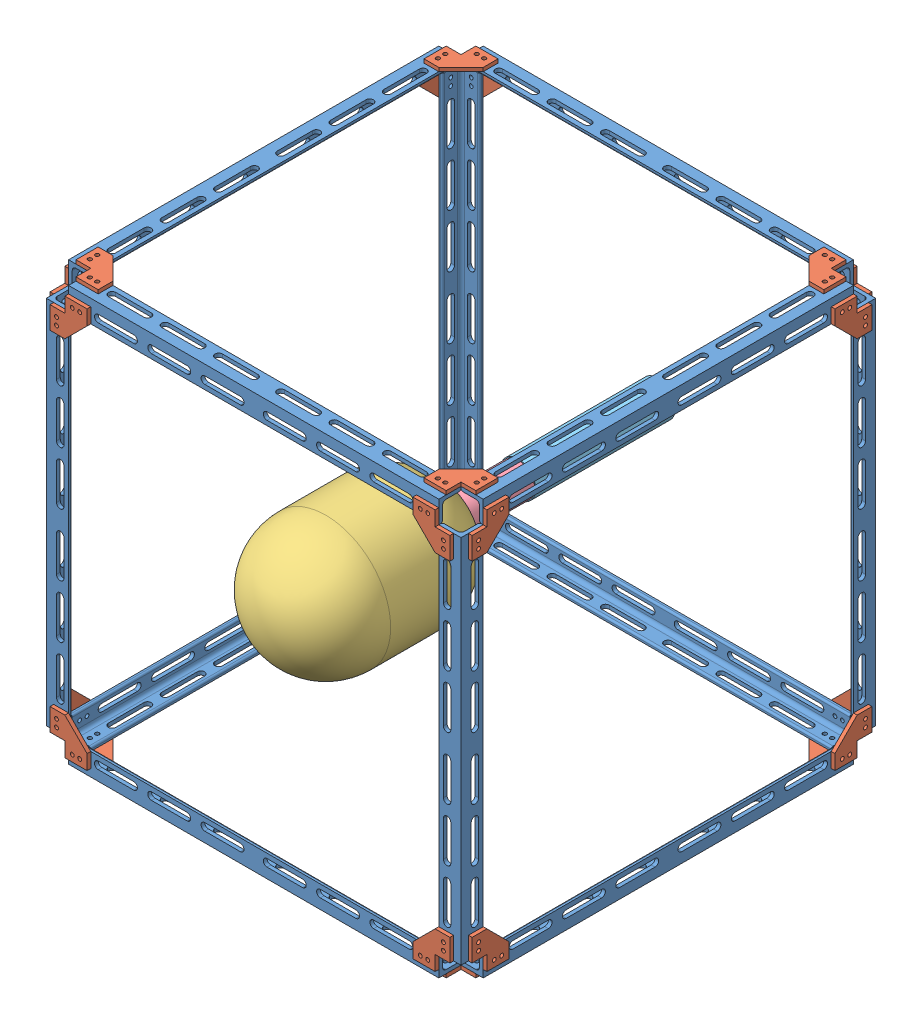
SolidWorks assembly Assem3, configuration Default. Lengths in mm.
Overall size (361.95 361.95 361.95).
41 component instances, 5 part files, 7 mates.
Components (placement in the parent):
- Outer struct 14 in side length-1: Outer struct 14 in side length [Default] at origin size (361.95 361.95 361.95)
  - WIP 14 inch .75 L rod-1: WIP 14 inch .75 L rod [8982K281] at (-9.525 9.525 0) size (19.05 19.05 317.5)
  - WIP bracket for .75 L bar-1: WIP bracket for .75 L bar [Default] at (-44.45 -3.175 -171.45) size (31.75 3.17 31.75)
  - WIP 14 inch .75 L rod-2: WIP 14 inch .75 L rod [8982K281] at (-177.8 9.525 -168.275) x (0 0 -1) z (1 0 0) size (19.05 19.05 317.5)
  - WIP 14 inch .75 L rod-3: WIP 14 inch .75 L rod [8982K281] at (-9.525 177.8 -168.275) x (1 0 0) z (0 -1 0) size (19.05 19.05 317.5)
  - WIP bracket for .75 L bar-2: WIP bracket for .75 L bar [Default] at (0 44.45 -171.45) x (0 -1 0) z (0 0 1) size (31.75 3.17 31.75)
  - WIP bracket for .75 L bar-3: WIP bracket for .75 L bar [Default] at (-44.45 6.35 -177.8) x (1 0 0) z (0 1 0) size (31.75 3.17 31.75)
  - WIP bracket for .75 L bar-4: WIP bracket for .75 L bar [Default] at (-311.15 349.25 -177.8) x (-1 0 0) z (0 -1 0) size (31.75 3.17 31.75)
  - WIP bracket for .75 L bar-5: WIP bracket for .75 L bar [Default] at (-355.6 311.15 -171.45) x (0 1 0) z (0 0 1) size (31.75 3.17 31.75)
  - WIP bracket for .75 L bar-6: WIP bracket for .75 L bar [Default] at (-311.15 358.775 -171.45) x (-1 0 0) z (0 0 1) size (31.75 3.17 31.75)
  - WIP 14 inch .75 L rod-4: WIP 14 inch .75 L rod [8982K281] at (-177.8 346.075 -168.275) x (0 0 -1) z (-1 0 0) size (19.05 19.05 317.5)
  - WIP 14 inch .75 L rod-5: WIP 14 inch .75 L rod [8982K281] at (-346.075 346.075 0) x (-1 0 0) z (0 0 1) size (19.05 19.05 317.5)
  - WIP 14 inch .75 L rod-6: WIP 14 inch .75 L rod [8982K281] at (-346.075 177.8 -168.275) x (-1 0 0) z (0 1 0) size (19.05 19.05 317.5)
  - WIP bracket for .75 L bar-8: WIP bracket for .75 L bar [Default] at (-6.35 311.15 -177.8) x (0 1 0) z (-1 0 0) size (31.75 3.17 31.75)
  - WIP bracket for .75 L bar-9: WIP bracket for .75 L bar [Default] at (-349.25 44.45 -177.8) x (0 -1 0) z (1 0 0) size (31.75 3.17 31.75)
  - WIP bracket for .75 L bar-11: WIP bracket for .75 L bar [Default] at (-6.35 355.6 133.35) x (0 0 1) z (-1 0 0) size (31.75 3.17 31.75)
  - WIP bracket for .75 L bar-12: WIP bracket for .75 L bar [Default] at (-44.45 349.25 177.8) x (1 0 0) z (0 -1 0) size (31.75 3.17 31.75)
  - WIP 14 inch .75 L rod-7: WIP 14 inch .75 L rod [8982K281] at (-177.8 346.075 168.275) x (0 0 1) z (1 0 0) size (19.05 19.05 317.5)
  - WIP 14 inch .75 L rod-8: WIP 14 inch .75 L rod [8982K281] at (-9.525 346.075 0) x (0 1 0) z (0 0 1) size (19.05 19.05 317.5)
  - WIP bracket for .75 L bar-13: WIP bracket for .75 L bar [Default] at (3.175 349.25 133.35) x (0 0 1) z (0 -1 0) size (31.75 3.17 31.75)
  - WIP 14 inch .75 L rod-9: WIP 14 inch .75 L rod [8982K281] at (-9.525 177.8 168.275) x (0 0 1) z (0 -1 0) size (19.05 19.05 317.5)
  - WIP bracket for .75 L bar-14: WIP bracket for .75 L bar [Default] at (3.175 311.15 -171.45) x (0 1 0) z (0 0 1) size (31.75 3.17 31.75)
  - WIP bracket for .75 L bar-15: WIP bracket for .75 L bar [Default] at (-349.25 358.775 133.35) x (0 0 1) z (1 0 0) size (31.75 3.17 31.75)
  - WIP bracket for .75 L bar-16: WIP bracket for .75 L bar [Default] at (-44.45 355.6 -171.45) size (31.75 3.17 31.75)
  - WIP bracket for .75 L bar-17: WIP bracket for .75 L bar [Default] at (-6.35 -3.175 133.35) x (0 0 1) z (-1 0 0) size (31.75 3.17 31.75)
  - WIP bracket for .75 L bar-18: WIP bracket for .75 L bar [Default] at (3.175 44.45 171.45) x (0 -1 0) z (0 0 -1) size (31.75 3.17 31.75)
  - WIP bracket for .75 L bar-19: WIP bracket for .75 L bar [Default] at (-349.25 311.15 177.8) x (0 1 0) z (1 0 0) size (31.75 3.17 31.75)
  - WIP bracket for .75 L bar-20: WIP bracket for .75 L bar [Default] at (-355.6 349.25 133.35) x (0 0 1) z (0 -1 0) size (31.75 3.17 31.75)
  - WIP bracket for .75 L bar-21: WIP bracket for .75 L bar [Default] at (-355.6 44.45 171.45) x (0 -1 0) z (0 0 -1) size (31.75 3.17 31.75)
  - WIP 14 inch .75 L rod-11: WIP 14 inch .75 L rod [8982K281] at (-346.075 177.8 168.275) x (-1 0 0) z (0 -1 0) size (19.05 19.05 317.5)
  - WIP bracket for .75 L bar-22: WIP bracket for .75 L bar [Default] at (-311.15 6.35 177.8) x (-1 0 0) z (0 1 0) size (31.75 3.17 31.75)
  - WIP 14 inch .75 L rod-12: WIP 14 inch .75 L rod [8982K281] at (-177.8 9.525 168.275) x (0 0 1) z (-1 0 0) size (19.05 19.05 317.5)
  - WIP bracket for .75 L bar-23: WIP bracket for .75 L bar [Default] at (-311.15 -3.175 171.45) x (-1 0 0) z (0 0 -1) size (31.75 3.17 31.75)
  - WIP 14 inch .75 L rod-13: WIP 14 inch .75 L rod [8982K281] at (-346.075 9.525 0) x (-1 0 0) z (0 0 -1) size (19.05 19.05 317.5)
  - WIP bracket for .75 L bar-24: WIP bracket for .75 L bar [Default] at (-355.6 6.35 -133.35) x (0 0 -1) z (0 1 0) size (31.75 3.17 31.75)
  - WIP bracket for .75 L bar-25: WIP bracket for .75 L bar [Default] at (-349.25 -3.175 -133.35) x (0 0 -1) z (1 0 0) size (31.75 3.17 31.75)
  - WIP bracket for .75 L bar-26: WIP bracket for .75 L bar [Default] at (-6.35 44.45 177.8) x (0 -1 0) z (-1 0 0) size (31.75 3.17 31.75)
- LoFi Tank+Reg-1: LoFi Tank+Reg [Default] at (-177.8 177.8 88.9) x (-0.987541 0.157359 0) z (0 0 1) size (111.12 111.12 340.27)
  - LoFi Tank-1: LoFi Tank [Default] at origin size (111.12 111.12 163.23)
  - LoFi Reg 1-1: LoFi Reg 1 [Default] at (0 0 -80.6816) x (-0.38598 0.922507 0) z (-0.922507 -0.38598 0) size (28.57 57.15 28.57)
  - LoFi Reg 2-1: LoFi Reg 2 [Default] at (0 0 -137.8316) x (-0.99247 0.12249 0) z (-0.12249 -0.99247 0) size (30.16 119.89 30.16)
Mates (geometry in assembly coordinates):
- Coincident3: coordinate: point of Outer struct 14 in side length-1
- Coincident4: coincident: circle of assembly; circle of LoFi Tank+Reg-1/LoFi Tank-1; plane of assembly
- Concentric2: concentric: cylinder of LoFi Tank+Reg-1/LoFi Reg 1-1 through (-177.8 177.8 -48.9316) axis (0 0 1) radius 14.2875
- Tangent2: tangent aligned: sphere of LoFi Tank+Reg-1/LoFi Tank-1
- Parallel2: parallel anti-aligned: plane of LoFi Tank+Reg-1/LoFi Reg 2-1 through (-177.8 177.8 -168.8196) normal (0 0 -1)
- Distance1: distance = 177.8 mm: cylinder of LoFi Tank+Reg-1/LoFi Reg 2-1 through (-177.8 177.8 -168.8196) axis (0 0 1) radius 15.0812; plane of Outer struct 14 in side length-1/WIP 14 inch .75 L rod-3 through (0 19.05 -177.8) normal (1 0 0)
- Distance2: distance = 177.8 mm: cylinder of LoFi Tank+Reg-1/LoFi Reg 2-1 through (-177.8 177.8 -168.8196) axis (0 0 1) radius 15.0812; plane of Outer struct 14 in side length-1/WIP 14 inch .75 L rod-13 through (-336.55 0 -158.75) normal (0 -1 0)
